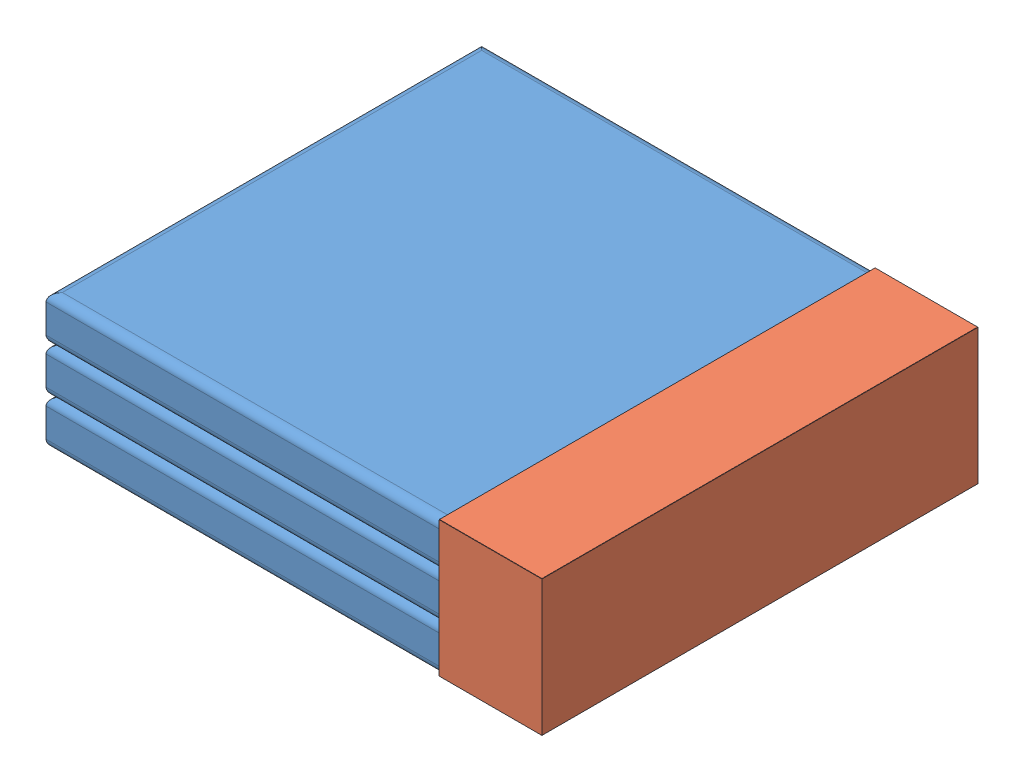
SolidWorks assembly LiPo 1-Cell 6Ah, configuration Default. Lengths in mm.
Overall size (60.53 16.55 53.2).
4 component instances, 2 part files, 4 mates.
Components (placement in the parent):
- LiPo Cell-1: LiPo Cell [Default] at (-54.3114 2.869 35.4544) size (60.5 5.5 53.15)
- LiPo Cell-2: LiPo Cell [Default] at (-54.3114 8.369 35.4544) size (60.5 5.5 53.15)
- LiPo Cell-3: LiPo Cell [Default] at (-54.3114 13.869 35.4544) size (60.5 5.5 53.15)
- Part1^LiPo 1-Cell 6Ah-1: Part1^LiPo 1-Cell 6Ah [Default] at (-54.3114 19.369 35.4544) x (-1 0 0) z (0 1 0) size (12.53 53.2 16.55) (virtual)
Mates (geometry in assembly coordinates):
- InPlace1: in place: plane of LiPo Cell-3 through (-54.3114 19.369 -17.6956) normal (0 1 0); plane of ? through (0 19.369 0) normal (0 1 0); moOrthogonalPlaneRef_w of LiPo Cell-3 through (-54.3114 19.369 -17.6956) normal (0 1 0); unknown of ?; plane of LiPo Cell-3 through (-54.3114 19.369 -17.6956) normal (0 1 0); line of ? through (-55 0 19.369) axis (0 -1 0); plane of LiPo Cell-3 through (-54.3114 19.369 -17.6956) normal (0 1 0); unknown of Part1^LiPo 1-Cell 6Ah-1
- Coincident1: coincident aligned: plane of LiPo Cell-3; plane of Part1^LiPo 1-Cell 6Ah-1
- Coincident2: coincident aligned: moOrthogonalPlaneRef_w of LiPo Cell-3 through (-54.3114 19.369 35.4544) normal (0 0 1); plane of Part1^LiPo 1-Cell 6Ah-1
- Coincident3: coincident anti-aligned: moOrthogonalPlaneRef_w of LiPo Cell-3 through (-54.3114 19.369 35.4544) normal (1 0 0); plane of Part1^LiPo 1-Cell 6Ah-1
